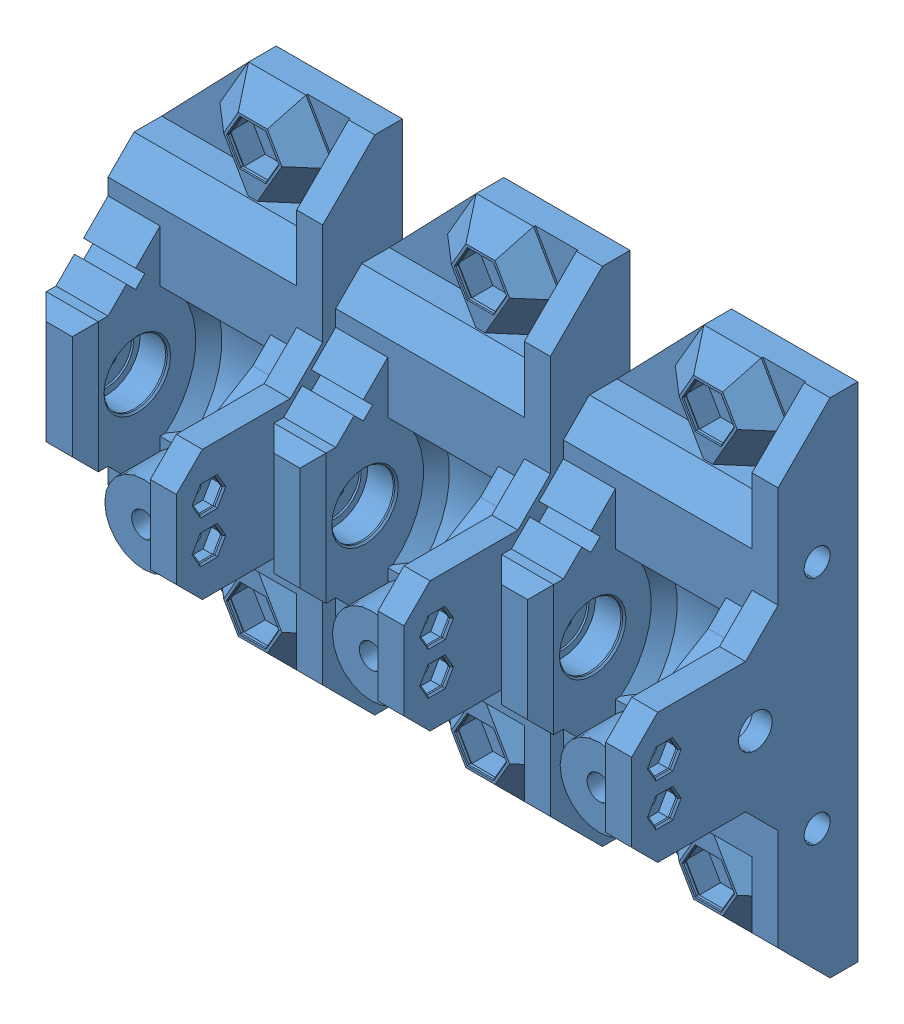
SolidWorks assembly idler_bracket-plate, configuration Default. Lengths in mm.
Overall size (103 77.25 34.75).
3 component instances, 1 part files, 9 mates.
Components (placement in the parent):
- Idler-bracket-1: Idler-bracket [Default] at (-196.5 0 549.75) x (1 0 0) z (0 1 0) size (33 34.75 77.25)
- Idler-bracket-2: Idler-bracket [Default] at (-161.5 0 549.75) x (1 0 0) z (0 1 0) size (33 34.75 77.25)
- Idler-bracket-3: Idler-bracket [Default] at (-231.5 0 549.75) x (1 0 0) z (0 1 0) size (33 34.75 77.25)
Mates (geometry in assembly coordinates):
- Coincident1: coincident anti-aligned: plane of Idler-bracket-2 through (-161.5 0 0) normal (0 0 -1); plane of assembly through (0 0 0) normal (0 0 1)
- Coincident3: coincident aligned: plane of Idler-bracket-2 through (-161.5 0 0) normal (0 0 -1); plane of Idler-bracket-1 through (-196.5 0 0) normal (0 0 -1)
- Distance1: distance = 2 mm: plane of Idler-bracket-3 through (-16.5 0 549.75) normal (1 0 0); plane of Idler-bracket-1 through (-14.5 0 549.75) normal (-1 0 0)
- Coincident4: coincident: plane of Idler-bracket-1 through (-196.5 0 549.75) normal (0 1 0); plane of Idler-bracket-3 through (-231.5 0 521.6112) normal (0 1 0)
- Distance2: distance = 2 mm anti-aligned: plane of Idler-bracket-2 through (20.5 0 549.75) normal (-1 0 0); plane of Idler-bracket-1 through (18.5 0 549.75) normal (1 0 0)
- Coincident6: coincident aligned: plane of Idler-bracket-1 through (-196.5 0 549.75) normal (0 1 0); plane of Idler-bracket-2 through (-161.5 0 549.75) normal (0 1 0)
- Coincident7: coincident: moEndPointRef_w of Idler-bracket-1; plane of assembly
- Coincident8: coincident aligned: plane of Idler-bracket-1 through (-196.5 0 549.75) normal (0 1 0); plane of assembly through (0 0 0) normal (0 1 0)
- Coincident10: coincident aligned: plane of Idler-bracket-1 through (-196.5 0 0) normal (0 0 -1); plane of Idler-bracket-3 through (-231.5 0 0) normal (0 0 -1)
